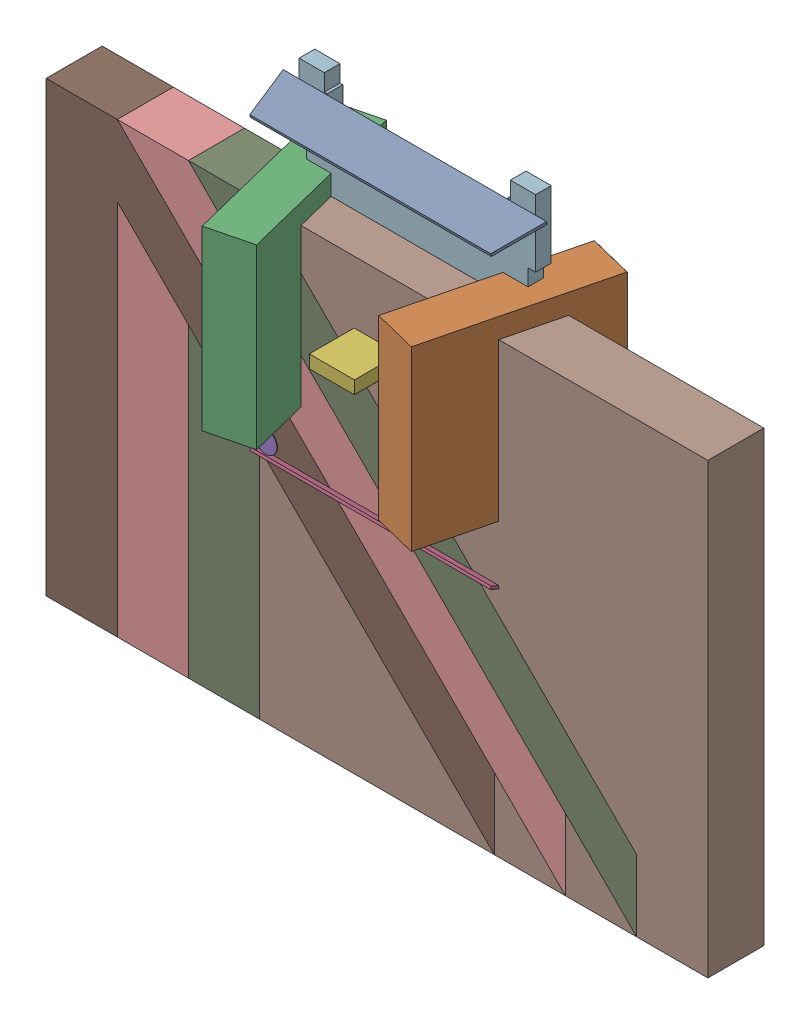
SolidWorks assembly PPAK-8, configuration ﾃﾞﾌｫﾙﾄ. Lengths in mm.
Overall size (11.81 9.85 3.29).
26 component instances, 7 part files, 0 mates.
Components (placement in the parent):
- User Library-DFN5x6_SO8FL-1: User Library-DFN5x6_SO8FL [ﾃﾞﾌｫﾙﾄ] at (-1.905 -2.74 0) size (11.81 9.85 3.29)
  - Free-Models-1: Free-Models [ﾃﾞﾌｫﾙﾄ] at origin size (11.81 9.85 3.29)
    - SIDE_S-1: SIDE_S [ﾃﾞﾌｫﾙﾄ] at (1.9 5.4223 0.705) x (1 0 0) z (0 0.970296 0.241922) size (4.7 0.82 0.05)
      - Extruded-1: Extruded [ﾃﾞﾌｫﾙﾄ] at origin size (4.7 0.82 0.05)
    - SIDE_L-1: SIDE_L [ﾃﾞﾌｫﾙﾄ] at (4.1508 2.775 0.705) x (0.241922 0 -0.970296) z (-0.970296 0 -0.241922) size (3.19 3.17 0.81)
      - Extruded_2-1: Extruded_2 [ﾃﾞﾌｫﾙﾄ] at origin size (3.19 3.17 0.81)
    - SIDE_L-1-1: SIDE_L-1 [ﾃﾞﾌｫﾙﾄ] at (-0.3508 2.775 0.705) x (-0.241922 0 -0.970296) z (0.970296 0 -0.241922) size (3.19 3.17 0.81)
      - Extruded_2-1: Extruded_2 [ﾃﾞﾌｫﾙﾄ] at origin size (3.19 3.17 0.81)
    - SIDE_S-1-1: SIDE_S-1 [ﾃﾞﾌｫﾙﾄ] at (1.9 0.1277 0.705) x (-1 0 0) z (0 -0.970296 0.241922) size (4.7 0.82 0.05)
      - Extruded-1: Extruded [ﾃﾞﾌｫﾙﾄ] at origin size (4.7 0.82 0.05)
    - 587257496-1: 587257496 [ﾃﾞﾌｫﾙﾄ] at (0.0484 0.4796 1.12) size (0.4 0.4 0.01)
      - Cylinder-1: Cylinder [ﾃﾞﾌｫﾙﾄ] at origin size (0.4 0.4 0.01)
    - 750905040-1: 750905040 [ﾃﾞﾌｫﾙﾄ] at (1.9 2.775 1) size (0.8 0.23 0.8)
      - Extruded_3-1: Extruded_3 [ﾃﾞﾌｫﾙﾄ] at origin size (0.8 0.23 0.8)
    - 266863104-1: 266863104 [ﾃﾞﾌｫﾙﾄ] at (1.9025 2.775 0.02) size (0.8 1.14 0.8)
      - Extruded_4-1: Extruded_4 [ﾃﾞﾌｫﾙﾄ] at origin size (0.8 1.14 0.8)
    - 500156144-1: 500156144 [ﾃﾞﾌｫﾙﾄ] at (3.81 0 0) size (8 8 1)
      - Extruded_5-1: Extruded_5 [ﾃﾞﾌｫﾙﾄ] at origin size (8 8 1)
    - 500156144-1-1: 500156144-1 [ﾃﾞﾌｫﾙﾄ] at (2.54 0 0) size (8 8 1)
      - Extruded_5-1: Extruded_5 [ﾃﾞﾌｫﾙﾄ] at origin size (8 8 1)
    - 500156144-2-1: 500156144-2 [ﾃﾞﾌｫﾙﾄ] at (1.27 0 0) size (8 8 1)
      - Extruded_5-1: Extruded_5 [ﾃﾞﾌｫﾙﾄ] at origin size (8 8 1)
    - 500156144-3-1: 500156144-3 [ﾃﾞﾌｫﾙﾄ] at origin size (8 8 1)
      - Extruded_5-1: Extruded_5 [ﾃﾞﾌｫﾙﾄ] at origin size (8 8 1)
    - 500160368-1: 500160368 [ﾃﾞﾌｫﾙﾄ] at (1.905 3.335 0) size (5.15 5.03 0.28)
      - Extruded_6-1: Extruded_6 [ﾃﾞﾌｫﾙﾄ] at origin size (5.15 5.03 0.28)
